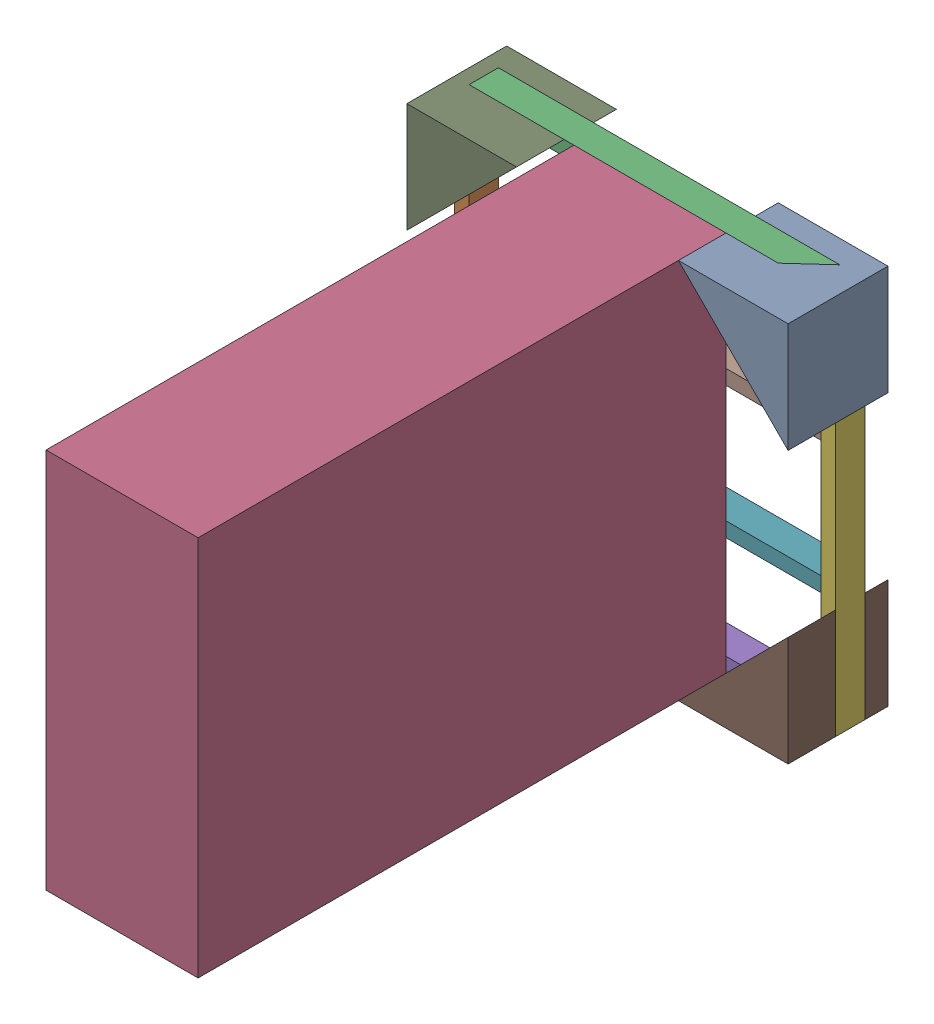
SolidWorks assembly Assem1, configuration Default. Lengths in mm.
Overall size (660.4 660.4 1004.95).
11 component instances, 4 part files, 25 mates.
Components (placement in the parent):
- Part1-1: Part1 [Default] at (304.7853 693.8432 -22.0905) x (0 -1 0) z (0 0 1) size (189.99 189.99 172.97)
- Part2-1: Part2 [Default] at (-165.6227 33.4432 17.6605) x (0 0 1) z (0 1 0) size (50.8 25.4 660.4)
- Part3-1: Part3 [Default] at (469.3773 668.4432 17.6605) x (0 0 1) z (-1 0 0) size (50.8 25.4 609.6)
- Part4-1: Part4 [Default] at (41.3873 33.4432 68.4605) size (263.4 660.4 914.4)
- Part3-2: Part3 [Default] at (-140.2227 58.8432 17.6605) x (0 0 1) z (1 0 0) size (50.8 25.4 609.6)
- Part2-3: Part2 [Default] at (494.7773 693.8432 17.6605) x (0 0 1) z (0 -1 0) size (50.8 25.4 660.4)
- Part3-3: Part3 [Default] at (-140.2227 262.0432 17.6605) x (0 0 1) z (1 0 0) size (50.8 25.4 609.6)
- Part3-4: Part3 [Default] at (-140.2227 490.6432 17.6605) x (0 0 1) z (1 0 0) size (50.8 25.4 609.6)
- Part1-2: Part1 [Default] at (-165.6227 503.8512 -22.0905) size (189.99 189.99 172.97)
- Part1-3: Part1 [Default] at (24.3693 33.4432 -22.0905) x (0 1 0) z (0 0 1) size (189.99 189.99 172.97)
- Part1-5: Part1 [Default] at (494.7773 223.4352 -22.0905) x (-1 0 0) z (0 0 1) size (189.99 189.99 172.97)
Mates (geometry in assembly coordinates):
- Coincident4: coincident aligned: line of Part2-1 through (-140.2227 693.8432 68.4605) axis (0 0 -1); line of Part3-1 through (-140.2227 693.8432 68.4605) axis (0 0 -1)
- Coincident5: coincident anti-aligned: line of Part2-1 through (-140.2227 693.8432 68.4605) axis (0 -1 0); line of Part3-1 through (-140.2227 668.4432 68.4605) axis (0 1 0)
- Coincident6: coincident aligned: line of Part3-2 through (469.3773 33.4432 68.4605) axis (0 0 -1); line of Part2-3 through (469.3773 33.4432 68.4605) axis (0 0 -1)
- Coincident7: coincident anti-aligned: line of Part3-2 through (469.3773 58.8432 68.4605) axis (0 -1 0); line of Part2-3 through (469.3773 33.4432 68.4605) axis (0 1 0)
- Coincident11: coincident aligned: line of Part3-1 through (469.3773 693.8432 68.4605) axis (0 0 -1); line of Part2-3 through (469.3773 693.8432 68.4605) axis (0 0 -1)
- Coincident12: coincident aligned: line of Part3-1 through (469.3773 668.4432 68.4605) axis (0 1 0); line of Part2-3 through (469.3773 33.4432 68.4605) axis (0 1 0)
- Coincident13: coincident anti-aligned: line of Part2-3 through (469.3773 33.4432 68.4605) axis (0 1 0); line of Part3-3 through (469.3773 262.0432 68.4605) axis (0 -1 0)
- Coincident14: coincident anti-aligned: line of Part2-3 through (469.3773 33.4432 68.4605) axis (0 1 0); line of Part3-4 through (469.3773 490.6432 68.4605) axis (0 -1 0)
- Distance1: distance = 203.2 mm: line of Part3-4 through (469.3773 465.2432 68.4605) axis (-1 0 0); line of Part3-3 through (469.3773 262.0432 68.4605) axis (-1 0 0)
- Width2: width anti-aligned: plane of Part3-2 through (469.3773 58.8432 17.6605) normal (0 1 0); plane of Part3-3 through (-140.2227 668.4432 17.6605) normal (0 -1 0); plane of Part3-1 through (469.3773 236.6432 17.6605) normal (0 -1 0); plane of Part3-4 through (469.3773 490.6432 17.6605) normal (0 1 0)
- Coincident16: coincident anti-aligned: line of Part1-1 through (494.7773 693.8432 150.8835) axis (0 0 -1); line of Part2-3 through (494.7773 693.8432 17.6605) axis (0 0 1)
- Coincident17: coincident aligned: plane of Part1-1 through (304.7853 693.8432 150.8835) normal (0 1 0); plane of Part3-1 through (-140.2227 693.8432 17.6605) normal (0 1 0)
- Distance2: distance = 39.751 mm aligned: plane of Part1-1 through (304.7853 693.8432 -22.0905) normal (0 0 -1); plane of Part3-1 through (-140.2227 668.4432 17.6605) normal (0 0 -1)
- Coincident19: coincident anti-aligned: line of Part2-1 through (-165.6227 693.8432 17.6605) axis (0 0 1); line of Part1-2 through (-165.6227 693.8432 150.8835) axis (0 0 -1)
- Coincident20: coincident aligned: plane of Part2-1 through (-165.6227 693.8432 17.6605) normal (-1 0 0); plane of Part1-2 through (-165.6227 503.8512 150.8835) normal (-1 0 0)
- Distance3: distance = 39.751 mm aligned: plane of Part1-2 through (-165.6227 503.8512 -22.0905) normal (0 0 -1); plane of Part3-1 through (-140.2227 668.4432 17.6605) normal (0 0 -1)
- Distance4: distance = 39.751 mm aligned: plane of Part1-3 through (24.3693 33.4432 -22.0905) normal (0 0 -1); plane of Part3-1 through (-140.2227 668.4432 17.6605) normal (0 0 -1)
- Coincident21: coincident anti-aligned: line of Part2-1 through (-165.6227 33.4432 17.6605) axis (0 0 1); line of Part1-3 through (-165.6227 33.4432 150.8835) axis (0 0 -1)
- Coincident22: coincident aligned: plane of Part3-2 through (469.3773 33.4432 17.6605) normal (0 -1 0); plane of Part1-3 through (24.3693 33.4432 150.8835) normal (0 -1 0)
- Distance6: distance = 39.751 mm aligned: plane of Part1-5 through (494.7773 223.4352 -22.0905) normal (0 0 -1); plane of Part3-1 through (-140.2227 668.4432 17.6605) normal (0 0 -1)
- Coincident23: coincident anti-aligned: line of Part2-3 through (494.7773 33.4432 17.6605) axis (0 0 1); line of Part1-5 through (494.7773 33.4432 150.8835) axis (0 0 -1)
- Coincident24: coincident aligned: plane of Part2-3 through (494.7773 33.4432 17.6605) normal (1 0 0); plane of Part1-5 through (494.7773 223.4352 150.8835) normal (1 0 0)
- Coincident25: coincident: line of Part1-1 through (304.7853 693.8432 150.8835) axis (0 0 -1); line of Part4-1 through (304.7853 693.8432 1320.9898) axis (0 0 -1)
- Coincident26: coincident: line of Part4-1 through (304.7853 33.4432 1320.9898) axis (0 0 -1); line of Part1-5 through (304.7853 33.4432 150.8835) axis (0 0 -1)
- Coincident30: coincident anti-aligned: line of Part4-1 through (41.3873 33.4432 68.4605) axis (1 0 0); line of Part3-2 through (469.3773 33.4432 68.4605) axis (-1 0 0)
